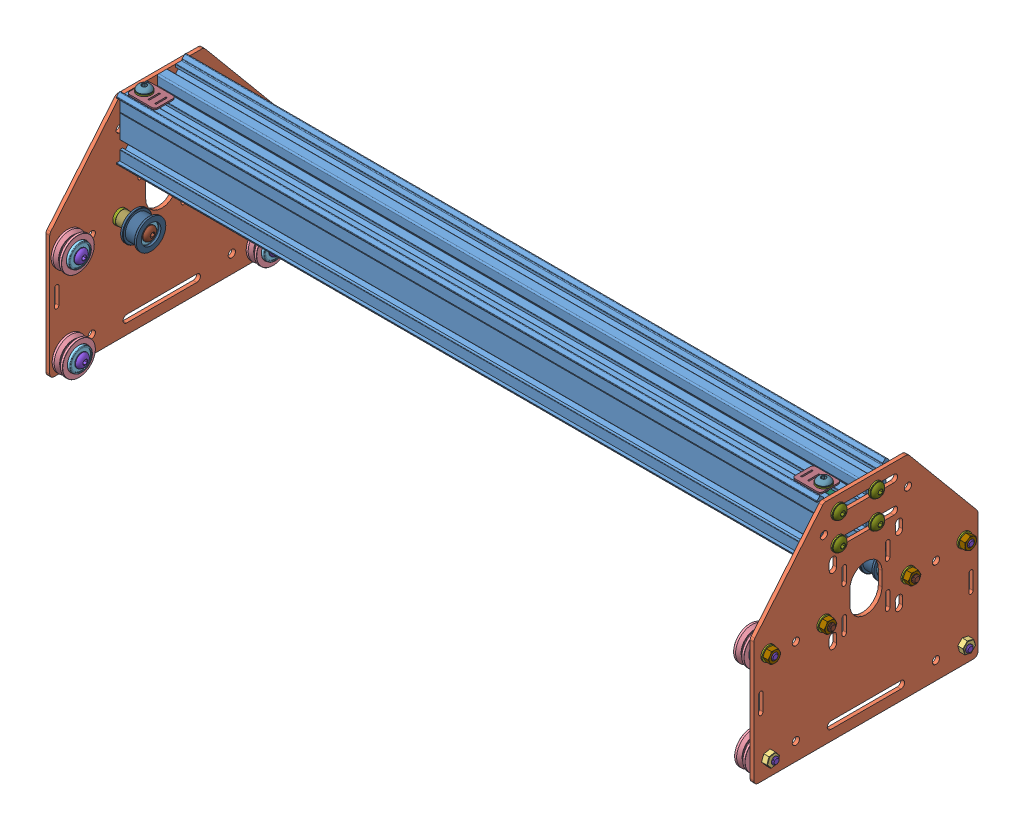
SolidWorks assembly S2_Gantry_500, configuration Default. Lengths in mm.
Overall size (518.52 155.81 165.72).
144 component instances, 16 part files, 48 mates.
Components (placement in the parent):
- 25142-XX500-1: 25142-XX500 [Default] at (-8.0439 3.5192 0) x (0 0 1) z (1 0 0) size (22.38 45.94 500)
- plate_assembly_stacked-1: plate_assembly_stacked [Default] at (-410.7007 -134.6852 70.9384) x (0 0 -1) z (1 0 0) size (164.61 150 32.91)
  - 26029-01-1: 26029-01 [Default] at origin size (160 150 2.66)
  - B18033-1: B18033 [Default] at (160.9384 20.9044 -3.9878) x (-0.352192 0.935928 0) z (0 0 1) size (9.18 7.95 5.26)
  - B18033-2: B18033 [Default] at (20.9384 20.9044 -3.9878) x (-0.283832 -0.958874 0) z (0 0 1) size (9.18 7.95 5.26)
  - 25203-02-1: 25203-02 [Default] at (20.9384 85.5044 9.0568) x (0.995036 -0.099517 0) z (-0.099517 -0.995036 0) size (23.5 11 23.5)
    - 25202-01-1: 25202-01 [Default] at origin size (23.5 7.5 23.5)
    - 25196-01-1: 25196-01 [Default] at (0 -3 0) x (0.224141 0 -0.974557) z (-0.974557 0 -0.224141) size (16 5 16)
    - 25201-01-1: 25201-01 [Default] at (0 -0.5 0) x (0.992075 0 -0.125646) z (0.125646 0 0.992075) size (10 1 10)
    - 25196-01-2: 25196-01 [Default] at (0 3 0) x (-0.996407 0 -0.084695) z (-0.084695 0 0.996407) size (16 5 16)
  - 25287-02-1: 25287-02 [Default] at (20.9384 85.5044 3.5568) size (10 10 0.9)
  - 91239A233-1: 91239A233 [Default] at (20.9384 85.5044 -5.4432) x (1 0 0) z (0 0 -1) size (9.5 9.5 22.91)
  - 25287-02-2: 25287-02 [Default] at (160.2015 20.6271 2.6568) x (-0.923728 -0.383049 0) z (0 0 -1) size (10 10 0.9)
  - 25284-02-1: 25284-02 [Default] at (20.9384 85.5044 -2.9) x (1 0 0) z (0 -1 0) size (8 4.29 9.24)
  - 25287-02-3: 25287-02 [Default] at (160.9384 85.5044 0) size (10 10 0.9)
  - 25287-02-4: 25287-02 [Default] at (160.9384 85.5044 3.5568) size (10 10 0.9)
  - 25287-02-5: 25287-02 [Default] at (21.6934 20.6809 2.6568) x (-0.923728 -0.383049 0) z (0 0 -1) size (10 10 0.9)
  - 25287-02-6: 25287-02 [Default] at (20.9384 85.5044 -0.9) x (1 0 0) z (0 0 -1) size (10 10 0.9)
  - 91239A233-2: 91239A233 [Default] at (21.6934 20.6809 -5.4432) x (1 0 0) z (0 0 -1) size (9.5 9.5 22.91)
  - 25203-02-2: 25203-02 [Default] at (21.6934 20.6809 9.0568) x (1 0 0) z (0 1 0) size (23.5 11 23.5)
    - 25202-01-1: 25202-01 [Default] at origin size (23.5 7.5 23.5)
    - 25196-01-1: 25196-01 [Default] at (0 -3 0) x (0.224141 0 -0.974557) z (-0.974557 0 -0.224141) size (16 5 16)
    - 25201-01-1: 25201-01 [Default] at (0 -0.5 0) x (0.992075 0 -0.125646) z (0.125646 0 0.992075) size (10 1 10)
    - 25196-01-2: 25196-01 [Default] at (0 3 0) x (-0.996407 0 -0.084695) z (-0.084695 0 0.996407) size (16 5 16)
  - 91239A233-3: 91239A233 [Default] at (160.2015 20.6271 -5.4432) x (1 0 0) z (0 0 -1) size (9.5 9.5 22.91)
  - 25203-02-3: 25203-02 [Default] at (160.2015 20.6271 9.0568) x (1 0 0) z (0 1 0) size (23.5 11 23.5)
    - 25202-01-1: 25202-01 [Default] at origin size (23.5 7.5 23.5)
    - 25196-01-1: 25196-01 [Default] at (0 -3 0) x (0.224141 0 -0.974557) z (-0.974557 0 -0.224141) size (16 5 16)
    - 25201-01-1: 25201-01 [Default] at (0 -0.5 0) x (0.992075 0 -0.125646) z (0.125646 0 0.992075) size (10 1 10)
    - 25196-01-2: 25196-01 [Default] at (0 3 0) x (-0.996407 0 -0.084695) z (-0.084695 0 0.996407) size (16 5 16)
  - 91239A233-4: 91239A233 [Default] at (160.9384 85.5044 -5.4432) x (1 0 0) z (0 0 -1) size (9.5 9.5 22.91)
  - 25203-02-4: 25203-02 [Default] at (160.9384 85.5044 9.0568) x (1 0 0) z (0 -1 0) size (23.5 11 23.5)
    - 25202-01-1: 25202-01 [Default] at origin size (23.5 7.5 23.5)
    - 25196-01-1: 25196-01 [Default] at (0 -3 0) x (0.224141 0 -0.974557) z (-0.974557 0 -0.224141) size (16 5 16)
    - 25201-01-1: 25201-01 [Default] at (0 -0.5 0) x (0.992075 0 -0.125646) z (0.125646 0 0.992075) size (10 1 10)
    - 25196-01-2: 25196-01 [Default] at (0 3 0) x (-0.996407 0 -0.084695) z (-0.084695 0 0.996407) size (16 5 16)
  - 25284-02-2: 25284-02 [Default] at (160.9384 85.5044 -2.9) x (0.037474 -0.999298 0) z (-0.999298 -0.037474 0) size (8 4.29 9.24)
  - 25197-02-1: 25197-02 [Default] at (128.9783 132.3034 54.0684) x (0 0 -1) z (-0.954972 -0.296697 0) size (12.6 21 21)
    - 25201-01-1: 25201-01 [Default] at (36.6716 43.7387 22.0081) x (0 1 0) z (0 0 1) size (10 1 10)
    - 25196-01-1: 25196-01 [Default] at (39.1716 43.7387 22.0081) x (0 1 0) z (0 0 1) size (16 5 16)
    - 25196-01-2: 25196-01 [Default] at (33.1716 43.7387 22.0081) x (0 1 0) z (0 0 1) size (16 5 16)
    - 25197-01-1: 25197-01 [Default] at (34.6716 43.7387 22.0081) size (11.2 21 21)
  - 25197-02-2: 25197-02 [Default] at (57.254 35.1797 54.0684) x (0 0 -1) z (0.92458 0.380987 0) size (12.6 21 21)
    - 25201-01-1: 25201-01 [Default] at (36.6716 43.7387 22.0081) x (0 1 0) z (0 0 1) size (10 1 10)
    - 25196-01-1: 25196-01 [Default] at (39.1716 43.7387 22.0081) x (0 1 0) z (0 0 1) size (16 5 16)
    - 25196-01-2: 25196-01 [Default] at (33.1716 43.7387 22.0081) x (0 1 0) z (0 0 1) size (16 5 16)
    - 25197-01-1: 25197-01 [Default] at (34.6716 43.7387 22.0081) size (11.2 21 21)
  - 25286-05-1: 25286-05 [Default] at (120.9384 84.0044 -6.6032) x (-0.651947 -0.758265 0) z (0 0 -1) size (9.5 9.5 32.91)
  - 25287-02-7: 25287-02 [Default] at (120.9384 84.0044 0) size (10 10 0.9)
  - 25284-02-3: 25284-02 [Default] at (120.9384 84.0044 -2.9) x (0.037474 -0.999298 0) z (-0.999298 -0.037474 0) size (8 4.29 9.24)
  - 25286-05-2: 25286-05 [Default] at (60.9384 84.0044 -6.6032) x (0.940642 0.3394 0) z (0 0 -1) size (9.5 9.5 32.91)
  - 25284-02-4: 25284-02 [Default] at (60.9384 84.0044 -2.9) x (-0.037474 0.999298 0) z (-0.999298 -0.037474 0) size (8 4.29 9.24)
  - 25287-02-8: 25287-02 [Default] at (60.9384 84.0044 0) x (-0.99589 0.090569 0) z (0 0 1) size (10 10 0.9)
  - 25312-14-1: 25312-14 [Default] at (60.9384 84.0044 4.4568) x (-0.162265 0.986747 0) z (0 0 1) size (9.53 9.53 7.94)
  - 25312-14-2: 25312-14 [Default] at (120.9384 84.0044 12.3968) x (0.519042 -0.854749 0) z (0 0 -1) size (9.53 9.53 7.94)
  - 25287-02-9: 25287-02 [Default] at (60.9384 84.0044 2.6568) x (0.999419 -0.034095 0) z (0 0 -1) size (10 10 0.9)
  - 25287-02-10: 25287-02 [Default] at (60.9384 84.0044 4.4568) x (0.999419 0.034095 0) z (0 0 1) size (10 10 0.9)
  - 25287-02-11: 25287-02 [Default] at (120.9384 84.0044 3.5568) x (0.999419 -0.034095 0) z (0 0 -1) size (10 10 0.9)
  - 25287-02-12: 25287-02 [Default] at (120.9384 84.0044 2.6568) x (0.999419 -0.034095 0) z (0 0 -1) size (10 10 0.9)
- plate_assembly_stacked-2: plate_assembly_stacked [Default] at (94.613 -134.6852 -110.9384) x (0 0 1) z (-1 0 0) size (164.61 150 32.91)
  - 26029-01-1: 26029-01 [Default] at origin size (160 150 2.66)
  - B18033-1: B18033 [Default] at (160.9384 20.9044 -3.9878) x (-0.352192 0.935928 0) z (0 0 1) size (9.18 7.95 5.26)
  - B18033-2: B18033 [Default] at (20.9384 20.9044 -3.9878) x (-0.283832 -0.958874 0) z (0 0 1) size (9.18 7.95 5.26)
  - 25203-02-1: 25203-02 [Default] at (20.9384 85.5044 9.0568) x (0.995036 -0.099517 0) z (-0.099517 -0.995036 0) size (23.5 11 23.5)
    - 25202-01-1: 25202-01 [Default] at origin size (23.5 7.5 23.5)
    - 25196-01-1: 25196-01 [Default] at (0 -3 0) x (0.224141 0 -0.974557) z (-0.974557 0 -0.224141) size (16 5 16)
    - 25201-01-1: 25201-01 [Default] at (0 -0.5 0) x (0.992075 0 -0.125646) z (0.125646 0 0.992075) size (10 1 10)
    - 25196-01-2: 25196-01 [Default] at (0 3 0) x (-0.996407 0 -0.084695) z (-0.084695 0 0.996407) size (16 5 16)
  - 25287-02-1: 25287-02 [Default] at (20.9384 85.5044 3.5568) size (10 10 0.9)
  - 91239A233-1: 91239A233 [Default] at (20.9384 85.5044 -5.4432) x (1 0 0) z (0 0 -1) size (9.5 9.5 22.91)
  - 25287-02-2: 25287-02 [Default] at (160.2015 20.6271 2.6568) x (-0.923728 -0.383049 0) z (0 0 -1) size (10 10 0.9)
  - 25284-02-1: 25284-02 [Default] at (20.9384 85.5044 -2.9) x (1 0 0) z (0 -1 0) size (8 4.29 9.24)
  - 25287-02-3: 25287-02 [Default] at (160.9384 85.5044 0) size (10 10 0.9)
  - 25287-02-4: 25287-02 [Default] at (160.9384 85.5044 3.5568) size (10 10 0.9)
  - 25287-02-5: 25287-02 [Default] at (21.6934 20.6809 2.6568) x (-0.923728 -0.383049 0) z (0 0 -1) size (10 10 0.9)
  - 25287-02-6: 25287-02 [Default] at (20.9384 85.5044 -0.9) x (1 0 0) z (0 0 -1) size (10 10 0.9)
  - 91239A233-2: 91239A233 [Default] at (21.6934 20.6809 -5.4432) x (1 0 0) z (0 0 -1) size (9.5 9.5 22.91)
  - 25203-02-2: 25203-02 [Default] at (21.6934 20.6809 9.0568) x (1 0 0) z (0 1 0) size (23.5 11 23.5)
    - 25202-01-1: 25202-01 [Default] at origin size (23.5 7.5 23.5)
    - 25196-01-1: 25196-01 [Default] at (0 -3 0) x (0.224141 0 -0.974557) z (-0.974557 0 -0.224141) size (16 5 16)
    - 25201-01-1: 25201-01 [Default] at (0 -0.5 0) x (0.992075 0 -0.125646) z (0.125646 0 0.992075) size (10 1 10)
    - 25196-01-2: 25196-01 [Default] at (0 3 0) x (-0.996407 0 -0.084695) z (-0.084695 0 0.996407) size (16 5 16)
  - 91239A233-3: 91239A233 [Default] at (160.2015 20.6271 -5.4432) x (1 0 0) z (0 0 -1) size (9.5 9.5 22.91)
  - 25203-02-3: 25203-02 [Default] at (160.2015 20.6271 9.0568) x (1 0 0) z (0 1 0) size (23.5 11 23.5)
    - 25202-01-1: 25202-01 [Default] at origin size (23.5 7.5 23.5)
    - 25196-01-1: 25196-01 [Default] at (0 -3 0) x (0.224141 0 -0.974557) z (-0.974557 0 -0.224141) size (16 5 16)
    - 25201-01-1: 25201-01 [Default] at (0 -0.5 0) x (0.992075 0 -0.125646) z (0.125646 0 0.992075) size (10 1 10)
    - 25196-01-2: 25196-01 [Default] at (0 3 0) x (-0.996407 0 -0.084695) z (-0.084695 0 0.996407) size (16 5 16)
  - 91239A233-4: 91239A233 [Default] at (160.9384 85.5044 -5.4432) x (1 0 0) z (0 0 -1) size (9.5 9.5 22.91)
  - 25203-02-4: 25203-02 [Default] at (160.9384 85.5044 9.0568) x (1 0 0) z (0 -1 0) size (23.5 11 23.5)
    - 25202-01-1: 25202-01 [Default] at origin size (23.5 7.5 23.5)
    - 25196-01-1: 25196-01 [Default] at (0 -3 0) x (0.224141 0 -0.974557) z (-0.974557 0 -0.224141) size (16 5 16)
    - 25201-01-1: 25201-01 [Default] at (0 -0.5 0) x (0.992075 0 -0.125646) z (0.125646 0 0.992075) size (10 1 10)
    - 25196-01-2: 25196-01 [Default] at (0 3 0) x (-0.996407 0 -0.084695) z (-0.084695 0 0.996407) size (16 5 16)
  - 25284-02-2: 25284-02 [Default] at (160.9384 85.5044 -2.9) x (0.037474 -0.999298 0) z (-0.999298 -0.037474 0) size (8 4.29 9.24)
  - 25197-02-1: 25197-02 [Default] at (128.9783 132.3034 54.0684) x (0 0 -1) z (-0.954972 -0.296697 0) size (12.6 21 21)
    - 25201-01-1: 25201-01 [Default] at (36.6716 43.7387 22.0081) x (0 1 0) z (0 0 1) size (10 1 10)
    - 25196-01-1: 25196-01 [Default] at (39.1716 43.7387 22.0081) x (0 1 0) z (0 0 1) size (16 5 16)
    - 25196-01-2: 25196-01 [Default] at (33.1716 43.7387 22.0081) x (0 1 0) z (0 0 1) size (16 5 16)
    - 25197-01-1: 25197-01 [Default] at (34.6716 43.7387 22.0081) size (11.2 21 21)
  - 25197-02-2: 25197-02 [Default] at (57.254 35.1797 54.0684) x (0 0 -1) z (0.92458 0.380987 0) size (12.6 21 21)
    - 25201-01-1: 25201-01 [Default] at (36.6716 43.7387 22.0081) x (0 1 0) z (0 0 1) size (10 1 10)
    - 25196-01-1: 25196-01 [Default] at (39.1716 43.7387 22.0081) x (0 1 0) z (0 0 1) size (16 5 16)
    - 25196-01-2: 25196-01 [Default] at (33.1716 43.7387 22.0081) x (0 1 0) z (0 0 1) size (16 5 16)
    - 25197-01-1: 25197-01 [Default] at (34.6716 43.7387 22.0081) size (11.2 21 21)
  - 25286-05-1: 25286-05 [Default] at (120.9384 84.0044 -6.6032) x (-0.651947 -0.758265 0) z (0 0 -1) size (9.5 9.5 32.91)
  - 25287-02-7: 25287-02 [Default] at (120.9384 84.0044 0) size (10 10 0.9)
  - 25284-02-3: 25284-02 [Default] at (120.9384 84.0044 -2.9) x (0.037474 -0.999298 0) z (-0.999298 -0.037474 0) size (8 4.29 9.24)
  - 25286-05-2: 25286-05 [Default] at (60.9384 84.0044 -6.6032) x (0.940642 0.3394 0) z (0 0 -1) size (9.5 9.5 32.91)
  - 25284-02-4: 25284-02 [Default] at (60.9384 84.0044 -2.9) x (-0.037474 0.999298 0) z (-0.999298 -0.037474 0) size (8 4.29 9.24)
  - 25287-02-8: 25287-02 [Default] at (60.9384 84.0044 0) x (-0.99589 0.090569 0) z (0 0 1) size (10 10 0.9)
  - 25312-14-1: 25312-14 [Default] at (60.9384 84.0044 4.4568) x (-0.162265 0.986747 0) z (0 0 1) size (9.53 9.53 7.94)
  - 25312-14-2: 25312-14 [Default] at (120.9384 84.0044 12.3968) x (0.519042 -0.854749 0) z (0 0 -1) size (9.53 9.53 7.94)
  - 25287-02-9: 25287-02 [Default] at (60.9384 84.0044 2.6568) x (0.999419 -0.034095 0) z (0 0 -1) size (10 10 0.9)
  - 25287-02-10: 25287-02 [Default] at (60.9384 84.0044 4.4568) x (0.999419 0.034095 0) z (0 0 1) size (10 10 0.9)
  - 25287-02-11: 25287-02 [Default] at (120.9384 84.0044 3.5568) x (0.999419 -0.034095 0) z (0 0 -1) size (10 10 0.9)
  - 25287-02-12: 25287-02 [Default] at (120.9384 84.0044 2.6568) x (0.999419 -0.034095 0) z (0 0 -1) size (10 10 0.9)
- belt_clip_assembly-1: belt_clip_assembly [Default] at (-395.5439 24.5192 0) x (0 0 1) z (0 1 0) size (15 22.5 10.91)
  - 26051-01-1: 26051-01 [Default] at origin size (15 20 1)
  - 91239A222-1: 91239A222 [Default] at (0 -5 -6.1) x (1 0 0) z (0 0 -1) size (9.5 9.5 10.91)
  - 25287-02-1: 25287-02 [Default] at (0 -5 1.9) size (10 10 0.9)
  - 26016-01-1: 26016-01 [Default] at (0 -5 -3) x (1 0 0) z (0 1 0) size (10 1.6 15)
- belt_clip_assembly-2: belt_clip_assembly [Default] at (79.4561 24.5192 0) x (0 0 -1) z (0 1 0) size (15 22.5 10.91)
  - 26051-01-1: 26051-01 [Default] at origin size (15 20 1)
  - 91239A222-1: 91239A222 [Default] at (0 -5 -6.1) x (1 0 0) z (0 0 -1) size (9.5 9.5 10.91)
  - 25287-02-1: 25287-02 [Default] at (0 -5 1.9) size (10 10 0.9)
  - 26016-01-1: 26016-01 [Default] at (0 -5 -3) x (1 0 0) z (0 1 0) size (10 1.6 15)
- 25286-02-1: 25286-02 [Default] at (83.513 13.5192 0) x (0 0 -1) z (-1 0 0) size (9.5 9.5 14.91)
- 25287-02-1: 25287-02 [Default] at (95.513 13.5192 0) x (0 0 -1) z (1 0 0) size (10 10 0.9)
- 25286-02-2: 25286-02 [Default] at (83.513 -6.4808 0) x (0 0 -1) z (-1 0 0) size (9.5 9.5 14.91)
- 25287-02-2: 25287-02 [Default] at (95.513 -6.4808 0) x (0 0 -1) z (1 0 0) size (10 10 0.9)
- 25286-02-3: 25286-02 [Default] at (-399.6007 -6.4808 0) x (0 0 1) z (1 0 0) size (9.5 9.5 14.91)
- 25287-02-3: 25287-02 [Default] at (-411.6007 -6.4808 0) x (0 0 1) z (-1 0 0) size (10 10 0.9)
- 25286-02-4: 25286-02 [Default] at (-399.6007 13.5192 0) x (0 0 1) z (1 0 0) size (9.5 9.5 14.91)
- 25287-02-4: 25287-02 [Default] at (-411.6007 13.5192 0) x (0 0 1) z (-1 0 0) size (10 10 0.9)
- 25142-XX500-2: 25142-XX500 [Default] at (-308.0439 3.5192 -26.8311) x (0 0 -1) z (-1 0 0) size (22.38 45.94 500)
- 25286-02-5: 25286-02 [Default] at (83.513 13.5192 -26.8311) x (0 0 -1) z (-1 0 0) size (9.5 9.5 14.91)
- 25287-02-5: 25287-02 [Default] at (95.513 13.5192 -26.8311) x (0 0 -1) z (1 0 0) size (10 10 0.9)
- 25286-02-6: 25286-02 [Default] at (83.513 -6.4808 -26.8311) x (0 0 -1) z (-1 0 0) size (9.5 9.5 14.91)
- 25287-02-6: 25287-02 [Default] at (95.513 -6.4808 -26.8311) x (0 0 -1) z (1 0 0) size (10 10 0.9)
- 25286-02-7: 25286-02 [Default] at (-399.6007 -6.4808 -26.8311) x (0 0 1) z (1 0 0) size (9.5 9.5 14.91)
- 25287-02-7: 25287-02 [Default] at (-411.6007 -6.4808 -26.8311) x (0 0 1) z (-1 0 0) size (10 10 0.9)
- 25286-02-8: 25286-02 [Default] at (-399.6007 13.5192 -26.8311) x (0 0 1) z (1 0 0) size (9.5 9.5 14.91)
- 25287-02-8: 25287-02 [Default] at (-411.6007 13.5192 -26.8311) x (0 0 1) z (-1 0 0) size (10 10 0.9)
Mates (geometry in assembly coordinates):
- Coincident1: coincident aligned: plane of 25142-XX500-1; plane of belt_clip_assembly-1/26051-01-1
- Coincident2: coincident anti-aligned: plane of 25142-XX500-1; plane of belt_clip_assembly-2/26051-01-1
- Coincident3: coincident anti-aligned: plane of 25142-XX500-1 through (-8.0439 21.5192 6) normal (0 -1 0); plane of belt_clip_assembly-2/26016-01-1 through (84.4561 21.5192 0) normal (0 1 0)
- Coincident4: coincident anti-aligned: plane of plate_assembly_stacked-2/26029-01-1 through (91.9561 -62.0359 -20) normal (-1 0 0); plane of belt_clip_assembly-2/26016-01-1 through (91.9561 21.5192 -5) normal (1 0 0)
- Coincident5: coincident anti-aligned: plane of plate_assembly_stacked-1/26029-01-1 through (-408.0439 -62.0359 -20) normal (1 0 0); plane of belt_clip_assembly-1/26016-01-1 through (-408.0439 21.5192 5) normal (-1 0 0)
- Coincident6: coincident anti-aligned: plane of 25142-XX500-1 through (-8.0439 21.5192 6) normal (0 -1 0); plane of belt_clip_assembly-1/26016-01-1 through (-400.5439 21.5192 0) normal (0 1 0)
- Coincident7: coincident anti-aligned: plane of plate_assembly_stacked-1/26029-01-1 through (-408.0439 -62.0359 -20) normal (1 0 0); plane of 25142-XX500-2 through (-408.0439 3.5192 -26.8311) normal (-1 0 0)
- Coincident8: coincident anti-aligned: plane of 25142-XX500-1 through (-408.0439 2.6691 0.3057) normal (-1 0 0); plane of plate_assembly_stacked-1/26029-01-1 through (-408.0439 -62.0359 -20) normal (1 0 0)
- Coincident9: coincident anti-aligned: plane of plate_assembly_stacked-2/26029-01-1 through (91.9561 -62.0359 -20) normal (-1 0 0); plane of 25142-XX500-2 through (91.9561 2.6691 -27.1368) normal (1 0 0)
- Coincident10: coincident anti-aligned: plane of 25142-XX500-1 through (91.9561 3.5192 0) normal (1 0 0); plane of plate_assembly_stacked-2/26029-01-1 through (91.9561 -62.0359 -20) normal (-1 0 0)
- Concentric1: concentric aligned: cylinder of 25142-XX500-1 through (91.9561 13.5192 0) axis (-1 0 0) radius 2.505; cylinder of plate_assembly_stacked-1/26029-01-1 through (-408.0439 13.5192 0) axis (-1 0 0) radius 2.625
- Concentric2: concentric aligned: cylinder of 25142-XX500-1 through (91.9561 -6.4808 0) axis (-1 0 0) radius 2.505; cylinder of plate_assembly_stacked-1/26029-01-1 through (-408.0439 -6.4808 0) axis (-1 0 0) radius 2.625
- Concentric3: concentric anti-aligned: cylinder of 25142-XX500-1 through (91.9561 13.5192 0) axis (-1 0 0) radius 2.505; cylinder of plate_assembly_stacked-2/26029-01-1 through (91.9561 13.5192 0) axis (1 0 0) radius 2.625
- Concentric4: concentric anti-aligned: cylinder of 25142-XX500-1 through (91.9561 -6.4808 0) axis (-1 0 0) radius 2.505; cylinder of plate_assembly_stacked-2/26029-01-1 through (91.9561 -6.4808 0) axis (1 0 0) radius 2.625
- Parallel1: parallel anti-aligned: plane of 25142-XX500-1; plane of 25142-XX500-2
- Concentric5: concentric anti-aligned: cylinder of 25286-02-5 through (98.263 13.5192 -26.8311) axis (-1 0 0) radius 4.75; cylinder of 25287-02-5 through (94.613 13.5192 -26.8311) axis (1 0 0) radius 5
- Concentric6: concentric anti-aligned: cylinder of 25286-02-1 through (98.263 13.5192 0) axis (-1 0 0) radius 4.75; cylinder of 25287-02-1 through (94.613 13.5192 0) axis (1 0 0) radius 5
- Concentric7: concentric anti-aligned: cylinder of 25286-02-6 through (98.263 -6.4808 -26.8311) axis (-1 0 0) radius 4.75; cylinder of 25287-02-6 through (94.613 -6.4808 -26.8311) axis (1 0 0) radius 5
- Concentric8: concentric anti-aligned: cylinder of 25286-02-2 through (98.263 -6.4808 0) axis (-1 0 0) radius 4.75; cylinder of 25287-02-2 through (94.613 -6.4808 0) axis (1 0 0) radius 2.65
- Coincident12: coincident anti-aligned: plane of 25286-02-2 through (95.513 -6.4808 0) normal (-1 0 0); plane of 25287-02-2 through (95.513 -6.4808 0) normal (1 0 0)
- Coincident13: coincident anti-aligned: plane of 25286-02-1 through (95.513 13.5192 0) normal (-1 0 0); plane of 25287-02-1 through (95.513 13.5192 0) normal (1 0 0)
- Coincident14: coincident anti-aligned: plane of 25286-02-5 through (95.513 13.5192 -26.8311) normal (-1 0 0); plane of 25287-02-5 through (95.513 13.5192 -26.8311) normal (1 0 0)
- Coincident15: coincident anti-aligned: plane of 25286-02-6 through (95.513 -6.4808 -26.8311) normal (-1 0 0); plane of 25287-02-6 through (95.513 -6.4808 -26.8311) normal (1 0 0)
- Concentric9: concentric aligned: cylinder of 25142-XX500-1 through (91.9561 13.5192 0) axis (-1 0 0) radius 2.505; cylinder of 25286-02-1 through (98.263 13.5192 0) axis (-1 0 0) radius 4.75
- Concentric10: concentric anti-aligned: cylinder of 25142-XX500-2 through (-408.0439 13.5192 -26.8311) axis (1 0 0) radius 2.505; cylinder of 25286-02-5 through (98.263 13.5192 -26.8311) axis (-1 0 0) radius 4.75
- Concentric11: concentric aligned: cylinder of 25142-XX500-1 through (91.9561 -6.4808 0) axis (-1 0 0) radius 2.505; cylinder of 25286-02-2 through (98.263 -6.4808 0) axis (-1 0 0) radius 4.75
- Concentric12: concentric anti-aligned: cylinder of 25142-XX500-2 through (-408.0439 -6.4808 -26.8311) axis (1 0 0) radius 2.505; cylinder of 25286-02-6 through (98.263 -6.4808 -26.8311) axis (-1 0 0) radius 4.75
- Coincident17: coincident aligned: plane of 25142-XX500-1 through (-8.0439 23.5192 -9) normal (0 1 0); plane of 25142-XX500-2 through (-308.0439 23.5192 -17.8311) normal (0 1 0)
- Coincident18: coincident anti-aligned: plane of plate_assembly_stacked-2/26029-01-1 through (94.613 -62.0359 -20) normal (1 0 0); plane of 25287-02-1 through (94.613 13.5192 0) normal (-1 0 0)
- Coincident19: coincident anti-aligned: plane of plate_assembly_stacked-2/26029-01-1 through (94.613 -62.0359 -20) normal (1 0 0); plane of 25287-02-2 through (94.613 -6.4808 0) normal (-1 0 0)
- Coincident20: coincident anti-aligned: plane of plate_assembly_stacked-2/26029-01-1 through (94.613 -62.0359 -20) normal (1 0 0); plane of 25287-02-6 through (94.613 -6.4808 -26.8311) normal (-1 0 0)
- Coincident21: coincident anti-aligned: plane of plate_assembly_stacked-2/26029-01-1 through (94.613 -62.0359 -20) normal (1 0 0); plane of 25287-02-5 through (94.613 13.5192 -26.8311) normal (-1 0 0)
- Concentric13: concentric anti-aligned: cylinder of 25286-02-4 through (-414.3507 13.5192 0) axis (1 0 0) radius 4.75; cylinder of 25287-02-4 through (-410.7007 13.5192 0) axis (-1 0 0) radius 2.65
- Concentric14: concentric anti-aligned: cylinder of 25286-02-8 through (-414.3507 13.5192 -26.8311) axis (1 0 0) radius 4.75; cylinder of 25287-02-8 through (-410.7007 13.5192 -26.8311) axis (-1 0 0) radius 2.65
- Concentric15: concentric anti-aligned: cylinder of 25286-02-7 through (-414.3507 -6.4808 -26.8311) axis (1 0 0) radius 4.75; cylinder of 25287-02-7 through (-410.7007 -6.4808 -26.8311) axis (-1 0 0) radius 2.65
- Concentric16: concentric anti-aligned: cylinder of 25286-02-3 through (-414.3507 -6.4808 0) axis (1 0 0) radius 4.75; cylinder of 25287-02-3 through (-410.7007 -6.4808 0) axis (-1 0 0) radius 2.65
- Coincident22: coincident anti-aligned: plane of 25286-02-8 through (-411.6007 13.5192 -26.8311) normal (1 0 0); plane of 25287-02-8 through (-411.6007 13.5192 -26.8311) normal (-1 0 0)
- Coincident23: coincident anti-aligned: plane of 25286-02-4 through (-411.6007 13.5192 0) normal (1 0 0); plane of 25287-02-4 through (-411.6007 13.5192 0) normal (-1 0 0)
- Coincident24: coincident anti-aligned: plane of 25286-02-7 through (-411.6007 -6.4808 -26.8311) normal (1 0 0); plane of 25287-02-7 through (-411.6007 -6.4808 -26.8311) normal (-1 0 0)
- Coincident25: coincident anti-aligned: plane of 25286-02-3 through (-411.6007 -6.4808 0) normal (1 0 0); plane of 25287-02-3 through (-411.6007 -6.4808 0) normal (-1 0 0)
- Concentric17: concentric aligned: cylinder of 25142-XX500-2 through (-408.0439 13.5192 -26.8311) axis (1 0 0) radius 2.505; cylinder of 25286-02-8 through (-414.3507 13.5192 -26.8311) axis (1 0 0) radius 4.75
- Concentric18: concentric anti-aligned: cylinder of 25142-XX500-1 through (91.9561 13.5192 0) axis (-1 0 0) radius 2.505; cylinder of 25286-02-4 through (-414.3507 13.5192 0) axis (1 0 0) radius 4.75
- Concentric19: concentric anti-aligned: cylinder of 25142-XX500-1 through (91.9561 -6.4808 0) axis (-1 0 0) radius 2.505; cylinder of 25286-02-3 through (-414.3507 -6.4808 0) axis (1 0 0) radius 4.75
- Concentric20: concentric aligned: cylinder of 25142-XX500-2 through (-408.0439 -6.4808 -26.8311) axis (1 0 0) radius 2.505; cylinder of 25286-02-7 through (-414.3507 -6.4808 -26.8311) axis (1 0 0) radius 4.75
- Coincident26: coincident anti-aligned: plane of plate_assembly_stacked-1/26029-01-1 through (-410.7007 -62.0359 -20) normal (-1 0 0); plane of 25287-02-7 through (-410.7007 -6.4808 -26.8311) normal (1 0 0)
- Coincident27: coincident anti-aligned: plane of plate_assembly_stacked-1/26029-01-1 through (-410.7007 -62.0359 -20) normal (-1 0 0); plane of 25287-02-3 through (-410.7007 -6.4808 0) normal (1 0 0)
- Coincident28: coincident anti-aligned: plane of plate_assembly_stacked-1/26029-01-1 through (-410.7007 -62.0359 -20) normal (-1 0 0); plane of 25287-02-8 through (-410.7007 13.5192 -26.8311) normal (1 0 0)
- Coincident29: coincident anti-aligned: plane of plate_assembly_stacked-1/26029-01-1 through (-410.7007 -62.0359 -20) normal (-1 0 0); plane of 25287-02-4 through (-410.7007 13.5192 0) normal (1 0 0)
